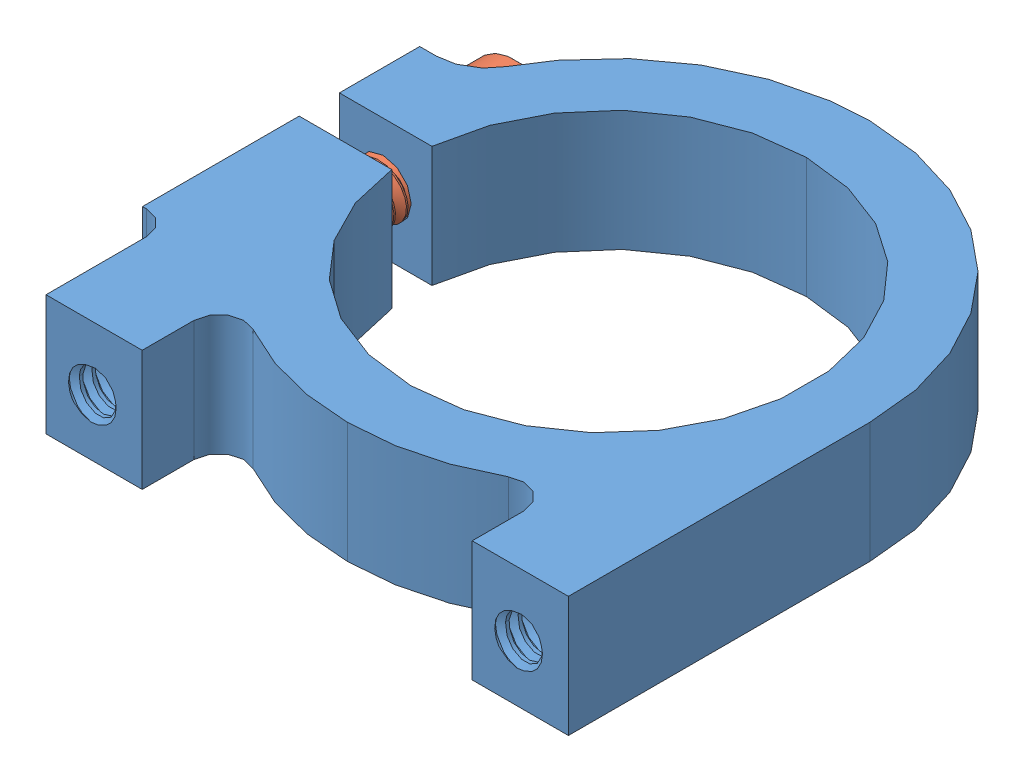
SolidWorks assembly 585716 assembly.STEP, configuration Default. Lengths in mm.
Overall size (34.9 7.62 35.56).
2 component instances, 2 part files, 0 mates.
Components (placement in the parent):
- 585716.STEP-1: 585716.STEP [Default] at (-26.5824 -0.3246 10.7212) size (34.8 7.62 35.56)
- 632114_90128A121.STEP-1: 632114_90128A121.STEP [Default] at (-42.1044 3.4854 17.0712) size (5.74 5.74 16.21)
